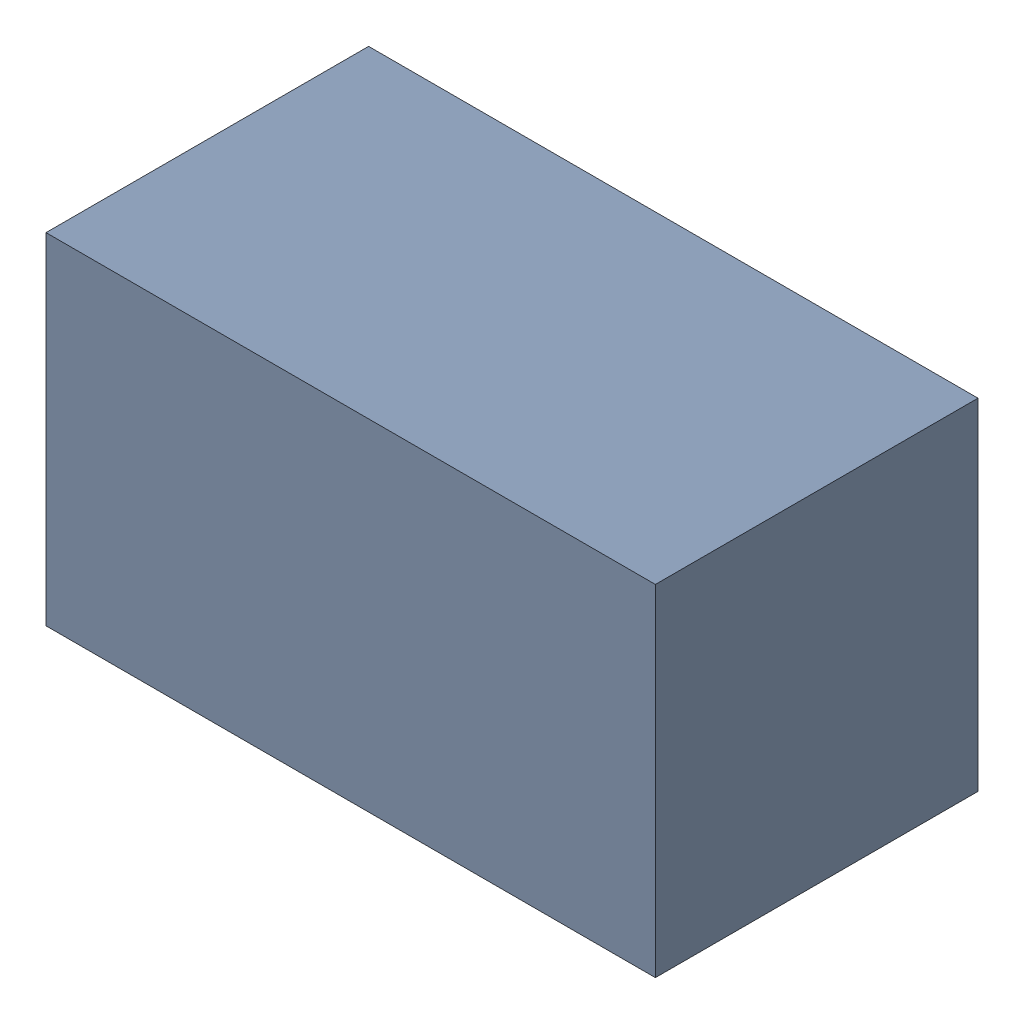
SolidWorks assembly R200, configuration Standard. Lengths in mm.
Overall size (1.7 0.95 0.9).
2 component instances, 1 part files, 0 mates.
Components (placement in the parent):
- 885541288-1: 885541288 [Standard] at (22.68 9.99 0) size (1.7 0.95 0.9)
  - Extruded_10-1: Extruded_10 [Standard] at origin size (1.7 0.95 0.9)
